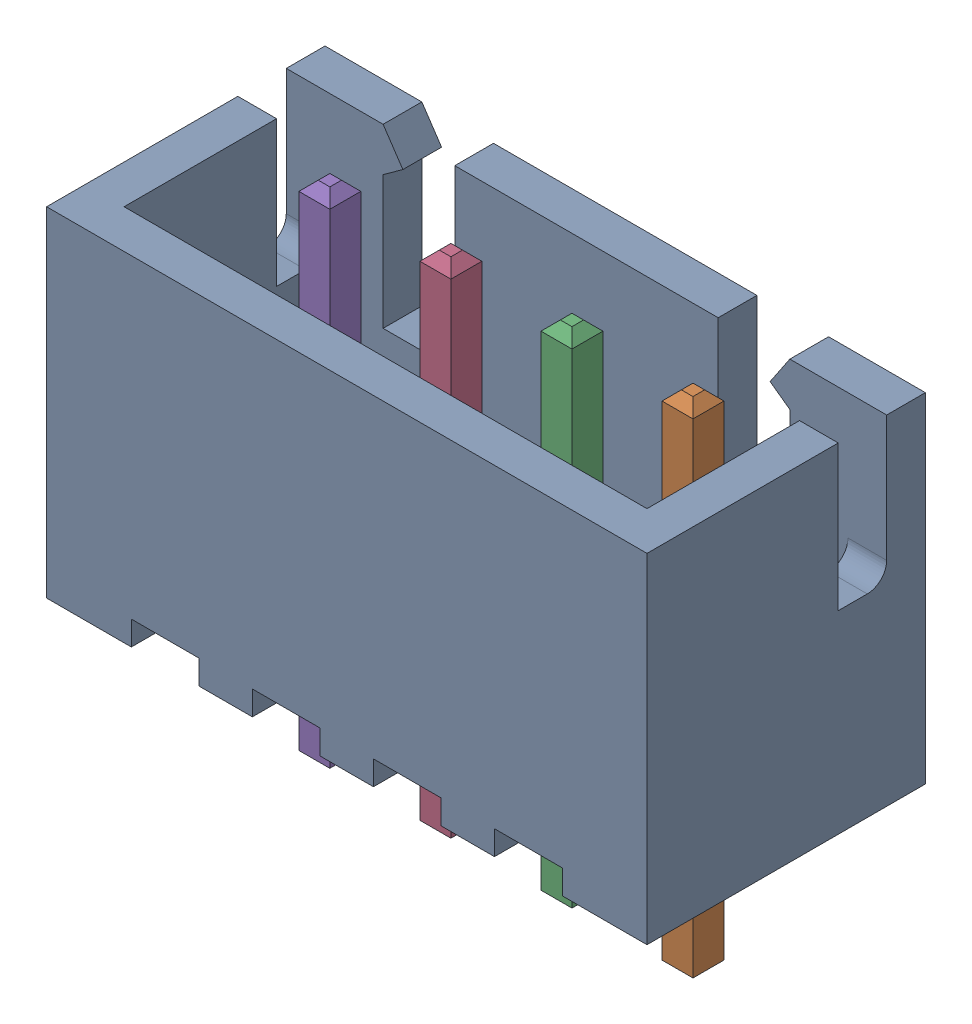
SolidWorks assembly 4 pin Header_1, configuration 4 pin Header_1. Lengths in mm.
Overall size (12.4 10.4 5.75).
5 component instances, 2 part files, 0 mates.
Components (placement in the parent):
- B4B-XH-A (BODY)-1: B4B-XH-A (BODY) [B4B-XH-A (BODY)] at (1.9192 5.3562 13.8157) size (12.4 7 5.75)
- B4B-XH-A (PIN)-1: B4B-XH-A (PIN) [B4B-XH-A (PIN)] at (5.6692 12.3562 13.2907) x (-1 0 0) z (0 0 1) size (0.64 10.4 0.64)
- B4B-XH-A (PIN)-2: B4B-XH-A (PIN) [B4B-XH-A (PIN)] at (3.1692 12.3562 13.2907) x (-1 0 0) z (0 0 1) size (0.64 10.4 0.64)
- B4B-XH-A (PIN)-3: B4B-XH-A (PIN) [B4B-XH-A (PIN)] at (0.6692 12.3562 13.2907) x (-1 0 0) z (0 0 1) size (0.64 10.4 0.64)
- B4B-XH-A (PIN)-4: B4B-XH-A (PIN) [B4B-XH-A (PIN)] at (-1.8308 12.3562 13.2907) x (-1 0 0) z (0 0 1) size (0.64 10.4 0.64)
